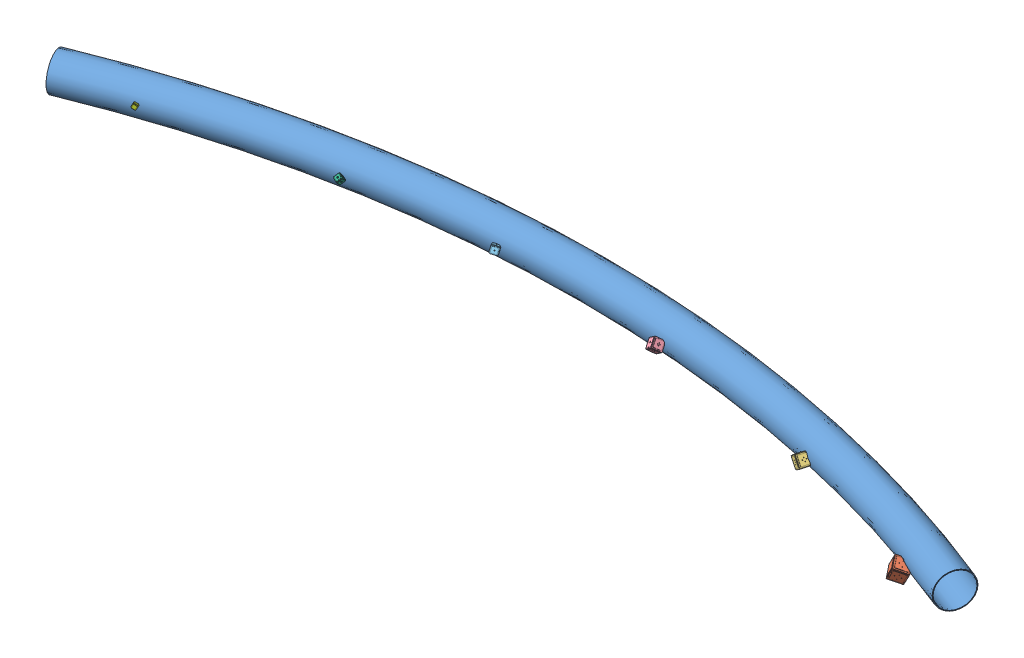
SolidWorks assembly tube3A, configuration Default. Lengths in mm.
Overall size (5554.54 175.44 6144.47).
8 component instances, 8 part files, 15 mates.
Components (placement in the parent):
- cube_positions-1: cube_positions [Default] at (-2670.6643 -3280.6684 6355.7547) x (0.67216 -0.00431 -0.740393) z (0.73275 0.147305 0.664364) (suppressed, hidden)
- tubes-1: tubes [tube3A] at origin size (5554.54 168.28 6144.47)
- cube_09-2: cube_09 [Default] at (1891.328 -39.9576 -219.9855) x (0.558213 -0.291956 0.776634) z (-0.686222 0.363684 0.629947) size (66.67 66.67 66.67)
- cube_10-2: cube_10 [Default] at (1228.5614 -17.4711 -418.2438) x (-0.71669 -0.609869 -0.338254) z (-0.59783 0.78702 -0.152311) size (53.98 55.56 54.09)
- cube_11-2: cube_11 [Default] at (417.5304 -1.7159 -528.0192) x (0.316006 -0.604945 0.730877) z (0.798081 0.586057 0.140015) size (46.52 46.39 46.35)
- cube_12-2: cube_12 [Default] at (-358.2393 3.7306 -535.1453) x (0.586492 0.345764 0.732445) z (-0.809811 0.233265 0.538324) size (33.65 33.65 33.65)
- cube_13-2: cube_13 [Default] at (-1020.6914 4.0423 -454.5155) x (0.910611 -0.27141 0.311647) z (0.00891 0.76683 0.641789) size (28.57 28.57 28.57)
- cube_14-2: cube_14 [Default] at (-1799.1926 16.7711 -254.42) x (0.802946 -0.45597 -0.383887) z (0.528044 0.2454 0.812987) size (20.96 20.96 20.96)
Mates (geometry in assembly coordinates):
- Coincident1: coincident aligned: plane of cube_positions-1 through (1952.5635 -154.6666 -280.8611) normal (0.686222 -0.363684 -0.629947); plane of ? through (1949.3113 -150.1135 -287.0323) normal (0.686222 -0.363684 -0.629947)
- Coincident2: coincident aligned: plane of cube_positions-1 through (1910.5222 -132.3856 -242.2675) normal (0.558213 -0.291956 0.776634); plane of ? through (1948.2953 -149.5442 -275.8676) normal (0.558213 -0.291956 0.776634)
- Coincident3: coincident aligned: plane of cube_positions-1 through (1904.8952 -60.3048 -290.0111) normal (0.466366 0.884588 -0.002666); plane of ? through (1971.2576 -95.2683 -282.1887) normal (0.466366 0.884588 -0.002666)
- Coincident13: coincident aligned: plane of cube_positions-1 through (310.08 -40.063 -555.0274) normal (0.798081 0.586057 0.140015); plane of ? through (328.9659 -58.2949 -586.3636) normal (0.798081 0.586057 0.140015)
- Coincident14: coincident aligned: plane of cube_positions-1 through (279.9164 -62.2132 -560.3193) normal (-0.513037 0.539053 0.667993); plane of ? through (265.0157 -39.299 -590.2545) normal (-0.513037 0.539053 0.667993)
- Coincident15: coincident aligned: plane of cube_positions-1 through (279.9164 -62.2132 -560.3193) normal (0.316006 -0.604945 0.730877); plane of ? through (280.8278 -66.9521 -564.6358) normal (0.316006 -0.604945 0.730877)
- Coincident16: coincident aligned: plane of cube_positions-1 through (-361.991 -26.3767 -569.4866) normal (-0.809811 0.233265 0.538324); plane of ? through (-365.0766 -6.1525 -582.8918) normal (-0.809811 0.233265 0.538324)
- Coincident17: coincident aligned: plane of cube_positions-1 through (-362.4288 -0.3367 -581.4287) normal (-0.015279 0.908864 -0.416812); plane of ? through (-341.6471 -8.7087 -600.4459) normal (-0.015279 0.908864 -0.416812)
- Coincident18: coincident aligned: plane of cube_positions-1 through (-361.991 -26.3767 -569.4866) normal (0.586492 0.345764 0.732445); plane of ? through (-338.4851 -33.4807 -584.955) normal (0.586492 0.345764 0.732445)
- Coincident25: coincident aligned: plane of cube_positions-1 through (-1038.7638 -16.3289 -494.2964) normal (-0.00891 -0.76683 -0.641789); plane of ? through (-1014.7963 -20.5635 -489.5696) normal (-0.00891 -0.76683 -0.641789)
- Coincident26: coincident aligned: plane of cube_positions-1 through (-1019.4252 -5.9096 -474.2445) normal (-0.413168 -0.581643 0.700702); plane of ? through (-1034.9685 -14.2841 -490.3611) normal (-0.413168 -0.581643 0.700702)
- Coincident30: coincident aligned: plane of cube_positions-1 through (1297.4563 -51.1161 -432.1099) normal (0.71669 0.609869 0.338254); plane of ? through (1325.3096 -83.5544 -432.6395) normal (0.71669 0.609869 0.338254)
- Coincident31: coincident aligned: plane of cube_positions-1 through (1291.6597 -119.2396 -441.178) normal (0.59783 -0.78702 0.152311); plane of ? through (1309.9848 -113.8713 -485.3661) normal (0.59783 -0.78702 0.152311)
- Coincident34: coincident aligned: plane of cube_positions-1 through (-1803.4939 5.8466 -279.6942) normal (0.528044 0.2454 0.812987); plane of ? through (-1786.555 14.0369 -293.1685) normal (0.528044 0.2454 0.812987)
- Coincident35: coincident aligned: plane of cube_positions-1 through (-1812.2937 1.7571 -293.2425) normal (-0.276492 -0.855494 0.437815); plane of ? through (-1812.1274 1.1585 -294.3072) normal (-0.276492 -0.855494 0.437815); sketch_entity of tubes-1
